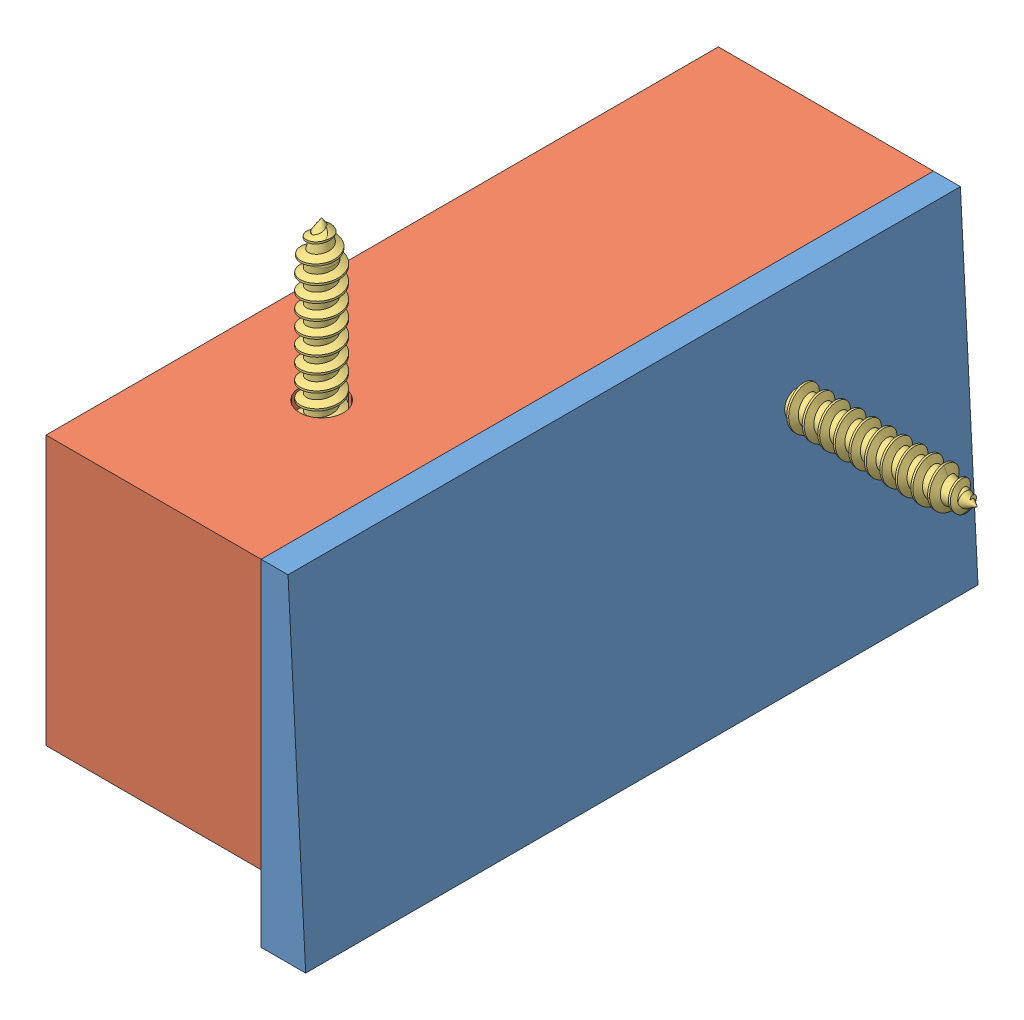
SolidWorks assembly Male Block Assembly, configuration Default. Lengths in mm.
Overall size (31.75 36.75 50).
4 component instances, 3 part files, 7 mates.
Components (placement in the parent):
- A3-1: A3 [Default] at (251.1241 2.6525 211.9133) x (1 0 0) z (0 0 -1) size (3.31 25 50)
- P4-1: P4 [Default] at (249.1241 -7.3475 186.9133) x (0 0 1) z (1 0 0) size (50 20 16)
- 90031A117_Phillips Flat Head Screws for Wood-1: 90031A117_Phillips Flat Head Screws for Wood [90031A117] at (241.1241 -1.4725 199.4133) x (0 1 0) z (0 0 1) size (31.75 5.71 5.71)
- 90031A117_Phillips Flat Head Screws for Wood-2: 90031A117_Phillips Flat Head Screws for Wood [90031A117] at (248.9991 -4.8475 174.4133) size (31.75 5.71 5.71)
Mates (geometry in assembly coordinates):
- Coincident140: coincident anti-aligned: plane of A3-1 through (249.1241 -22.3475 161.9133) normal (-1 0 0); plane of P4-1 through (249.1241 -7.3475 186.9133) normal (1 0 0)
- Coincident141: coincident aligned: line of A3-1 through (249.1241 2.6525 161.9133) axis (0 0 1); line of P4-1 through (249.1241 2.6525 161.9133) axis (0 0 1)
- Coincident142: coincident aligned: line of A3-1 through (249.1241 -22.3475 211.9133) axis (0 1 0); line of P4-1 through (249.1241 -17.3475 211.9133) axis (0 1 0)
- Concentric1: concentric aligned: circle of P4-1; cylinder of 90031A117_Phillips Flat Head Screws for Wood-1 through (241.1241 -17.3475 199.4133) axis (0 -1 0) radius 1.4224
- Coincident143: coincident aligned: plane of P4-1 through (233.1241 -17.3475 161.9133) normal (0 -1 0); circle of 90031A117_Phillips Flat Head Screws for Wood-1
- Concentric2: concentric aligned: circle of P4-1; cylinder of 90031A117_Phillips Flat Head Screws for Wood-2 through (233.1241 -4.8475 174.4133) axis (-1 0 0) radius 1.4224
- Coincident144: coincident aligned: plane of P4-1 through (233.1241 -7.3475 186.9133) normal (-1 0 0); plane of 90031A117_Phillips Flat Head Screws for Wood-2 through (233.1241 -4.8475 174.4133) normal (-1 0 0)
